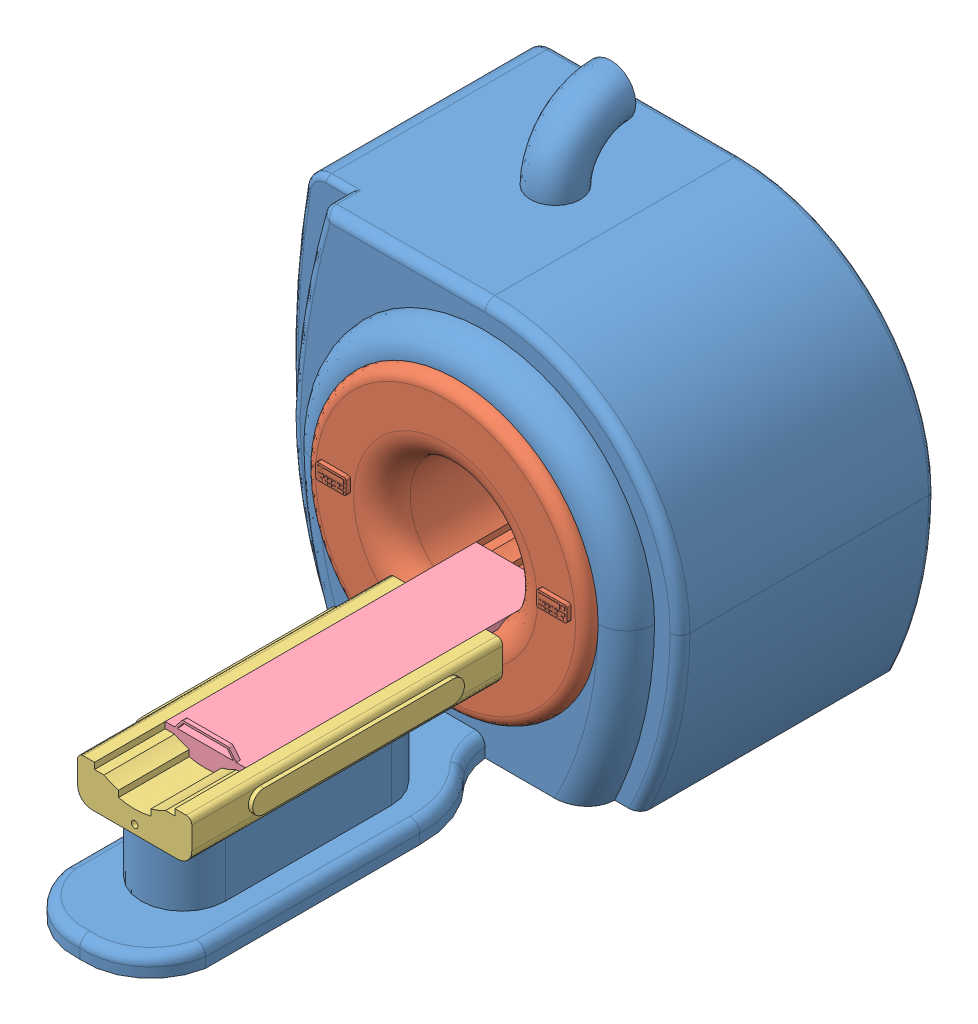
SolidWorks assembly MRI scanner, configuration Default. Lengths in mm.
Overall size (294.65 316.99 467.51).
4 component instances, 4 part files, 8 mates.
Components (placement in the parent):
- Base Frame-1: Base Frame [Default] at (215.0742 187.8159 122.1083) size (294.65 316.99 467.51)
- Center Part-1: Center Part [Default] at (215.0742 187.8159 130.1083) size (200 200 211.2)
- Bed Base-1: Bed Base [Default] at (186.6426 152.9355 330.1083) size (86.86 30 220)
- Moving Bed-1: Moving Bed [Default] at (186.6426 152.9355 280.0733) size (56.86 21.3 220)
Mates (geometry in assembly coordinates):
- Concentric1: concentric aligned: cylinder of Base Frame-1 through (215.0742 187.8159 322.1083) axis (0 0 -1) radius 100; cylinder of Center Part-1 through (215.0742 187.8159 330.1083) axis (0 0 -1) radius 100
- Coincident1: coincident anti-aligned: circle of Base Frame-1; circle of Center Part-1
- Lock1: lock: unknown of Base Frame-1; unknown of Center Part-1
- Coincident2: coincident aligned: line of Center Part-1 through (243.5058 152.9355 310.1083) axis (0 0 -1); line of Bed Base-1 through (243.5058 152.9355 550.1083) axis (0 0 -1)
- Coincident3: coincident aligned: line of Center Part-1 through (186.6426 152.9355 310.1083) axis (0 0 -1); line of Bed Base-1 through (186.6426 152.9355 550.1083) axis (0 0 -1)
- Coincident4: coincident anti-aligned: plane of Center Part-1 through (215.0742 187.8159 330.1083) normal (0 0 1); plane of Bed Base-1 through (186.6426 152.9355 330.1083) normal (0 0 -1)
- Coincident5: coincident aligned: line of Bed Base-1 through (243.5058 148.4548 550.1083) axis (0 0 -1); line of Moving Bed-1 through (243.5058 148.4548 500.0733) axis (0 0 -1)
- Coincident6: coincident aligned: line of Bed Base-1 through (186.6426 148.4548 550.1083) axis (0 0 -1); line of Moving Bed-1 through (186.6426 148.4548 500.0733) axis (0 0 -1)
